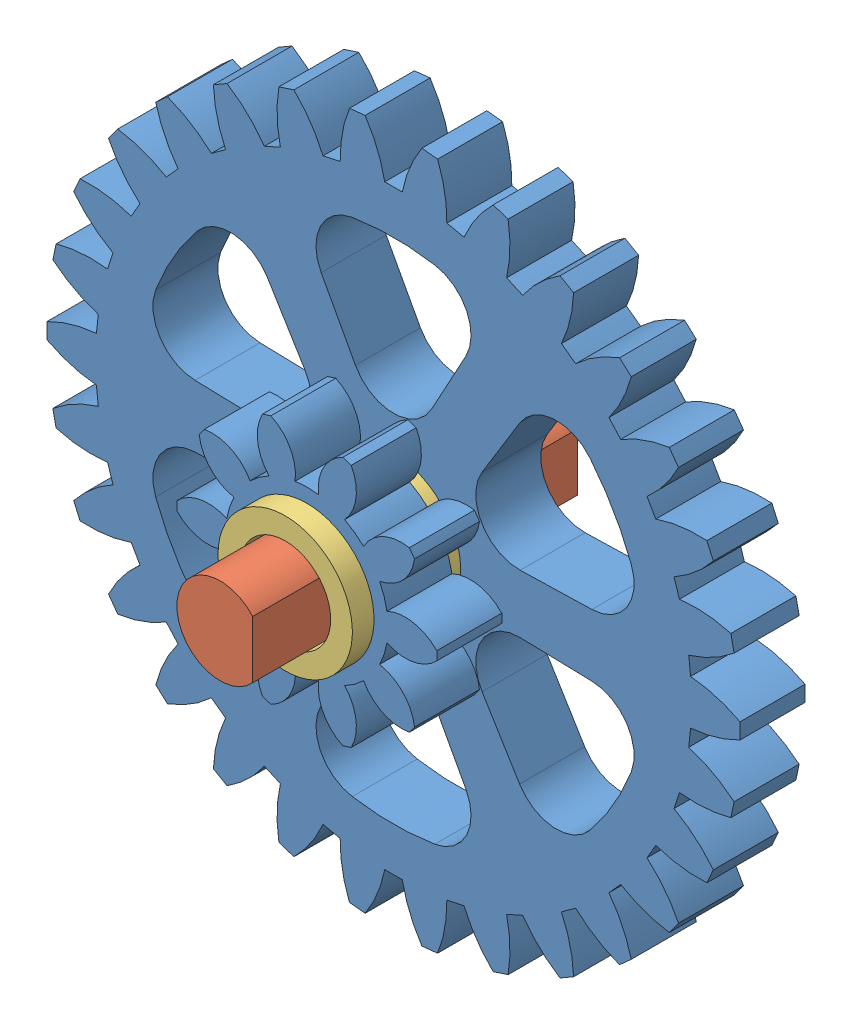
SolidWorks assembly Subassembly 2, configuration Default. Lengths in mm.
Overall size (32 31.89 15).
6 component instances, 3 part files, 12 mates.
Components (placement in the parent):
- root gear assignment-1: root gear assignment [30T 1.0Mod] at (13.4314 26.1825 3.4966) size (32 31.89 3)
- root gear assignment-2: root gear assignment [10T 1.5Mod] at (13.4314 26.1825 7.4966) size (18 17.3 3)
- axle-1: axle [15mm axle] at (13.4314 26.1825 -0.5034) x (-1 0 0) z (0 0 1) size (3.5 4 15)
- Spacer-1: Spacer [4.2-1] at (13.4314 26.1825 10.4966) size (6.2 6.2 1)
- Spacer-3: Spacer [4.2-1] at (13.4314 26.1825 6.4966) size (6.2 6.2 1)
- Spacer-4: Spacer [4.2-1] at (13.4314 26.1825 2.4966) size (6.2 6.2 1)
Mates (geometry in assembly coordinates):
- Concentric1: concentric aligned: cylinder of root gear assignment-2 through (13.4314 26.1825 10.4966) axis (0 0 -1) radius 2; cylinder of axle-1 through (13.4314 26.1825 14.4966) axis (0 0 -1) radius 2
- Coincident1: coincident anti-aligned: plane of root gear assignment-2 through (14.9314 27.5054 10.4966) normal (-1 0 0); plane of axle-1 through (14.9314 24.8596 14.4966) normal (1 0 0)
- Concentric2: concentric aligned: cylinder of axle-1 through (13.4314 26.1825 14.4966) axis (0 0 -1) radius 2; cylinder of Spacer-1 through (13.4314 26.1825 11.4966) axis (0 0 -1) radius 2.1
- Coincident2: coincident anti-aligned: plane of root gear assignment-2 through (13.4314 26.1825 10.4966) normal (0 0 1); plane of Spacer-1 through (13.4314 26.1825 10.4966) normal (0 0 -1)
- Distance1: distance = 3 mm aligned: plane of Spacer-1 through (13.4314 26.1825 11.4966) normal (0 0 1); plane of axle-1 through (13.4314 26.1825 14.4966) normal (0 0 1)
- Concentric3: concentric aligned: cylinder of root gear assignment-1 through (13.4314 26.1825 6.4966) axis (0 0 -1) radius 2; cylinder of axle-1 through (13.4314 26.1825 14.4966) axis (0 0 -1) radius 2
- Coincident3: coincident anti-aligned: plane of root gear assignment-1 through (14.9314 27.5054 6.4966) normal (-1 0 0); plane of axle-1 through (14.9314 24.8596 14.4966) normal (1 0 0)
- Concentric4: concentric aligned: cylinder of axle-1 through (13.4314 26.1825 14.4966) axis (0 0 -1) radius 2; cylinder of Spacer-3 through (13.4314 26.1825 7.4966) axis (0 0 -1) radius 2.1
- Coincident4: coincident anti-aligned: plane of root gear assignment-2 through (13.4314 26.1825 7.4966) normal (0 0 -1); plane of Spacer-3 through (13.4314 26.1825 7.4966) normal (0 0 1)
- Coincident5: coincident anti-aligned: plane of root gear assignment-1 through (13.4314 26.1825 6.4966) normal (0 0 1); plane of Spacer-3 through (13.4314 26.1825 6.4966) normal (0 0 -1)
- Concentric5: concentric aligned: cylinder of axle-1 through (13.4314 26.1825 14.4966) axis (0 0 -1) radius 2; cylinder of Spacer-4 through (13.4314 26.1825 3.4966) axis (0 0 -1) radius 2.1
- Coincident6: coincident anti-aligned: plane of root gear assignment-1 through (13.4314 26.1825 3.4966) normal (0 0 -1); plane of Spacer-4 through (13.4314 26.1825 3.4966) normal (0 0 1)
